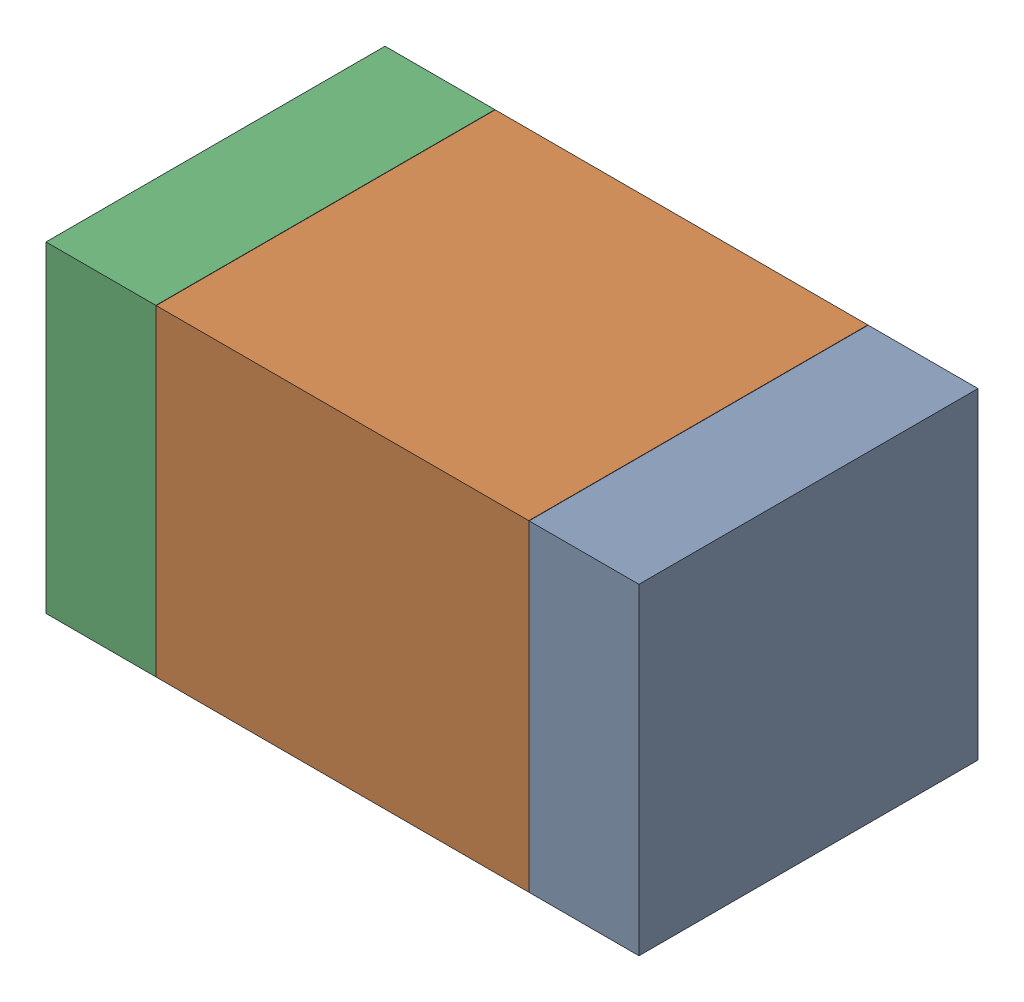
SolidWorks assembly R13, configuration Default. Lengths in mm.
Overall size (1.75 0.95 1).
6 component instances, 2 part files, 0 mates.
Components (placement in the parent):
- 6575498272-1: 6575498272 [Default] at (16.7285 23.876 0) size (0.32 0.95 1)
  - Extruded_8-1: Extruded_8 [Default] at origin size (0.32 0.95 1)
- 6575498112-1: 6575498112 [Default] at (16.016 23.876 0) size (1.1 0.95 1)
  - Extruded_9-1: Extruded_9 [Default] at origin size (1.1 0.95 1)
- 6575498272-2: 6575498272 [Default] at (15.3035 23.876 0) size (0.32 0.95 1)
  - Extruded_8-1: Extruded_8 [Default] at origin size (0.32 0.95 1)
